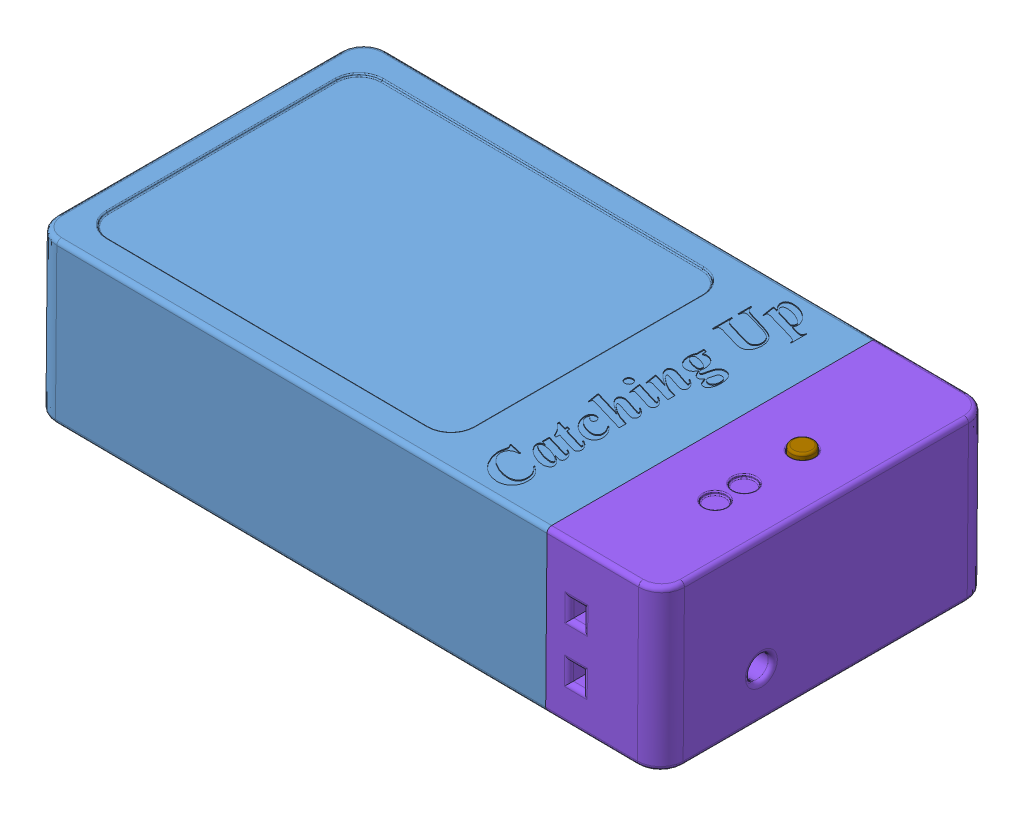
SolidWorks assembly Assemblage2, configuration Défaut. Lengths in mm.
Overall size (137.3 36.19 72).
11 component instances, 9 part files, 7 mates.
Components (placement in the parent):
- boitierHaut-1: boitierHaut [Défaut] at (21.3672 20.9125 31) x (-0.999962 0.008727 0) z (0 0 1) size (119 35 72)
- Assemblage3-1: Assemblage3 [Défaut] at (-20.9673 14.1434 2.8937) x (-0.999962 0.008727 0) z (-0.000152 -0.017452 -0.999848) size (120.99 30.31 52.25)
  - bouton-1: bouton [Défaut] at (-61.2589 -5.3974 3.7359) x (0 0.017452 0.999848) z (-1 0 0) size (13 7.1 12)
  - circuit-1: circuit [Défaut] at (-60.3389 -5.8468 -22.0102) x (1 0 0) z (0 -0.999848 0.017452) size (50 50 1.6)
  - lecteur rfid-1: lecteur rfid [Défaut] at (-17.2739 1.0424 28.8799) x (1 0 0) z (0 0.017452 0.999848) size (112 15 52)
  - module rf-1: module rf [Défaut] at (-26.2716 -8.8392 12.8286) x (1 0 0) z (0 -0.017452 -0.999848) size (29 15 15)
  - red-led-5mm-1: red-led-5mm [Default] at (-55.2587 -4.9394 -2.9734) x (1 0 0) z (0 0.999848 -0.017452) size (5.95 5.62 28.7)
  - User Library-ArduinoMicro-1: User Library-ArduinoMicro [Default] at (-37.4535 -9.5207 4.728) x (0 -0.017452 -0.999848) z (-1 0 0) size (49.28 17.35 17.83)
  - red-led-5mm-2: red-led-5mm [Default] at (-55.2588 -5.0502 -9.3222) x (1 0 0) z (0 0.999848 -0.017452) size (5.95 5.62 28.7)
- Pièce2^Assemblage2-1: Pièce2^Assemblage2 [Défaut] at (21.1098 -8.5864 31) x (-0.999962 0.008727 0) z (-0.008727 -0.999962 0) size (135 72 35) (virtual)
- Pièce1^Assemblage2-1: Pièce1^Assemblage2 [Défaut] at (-69.4127 21.7047 0) x (0.999962 -0.008727 0) z (0.008727 0.999962 0) size (5.69 5.69 10) (virtual)
Mates (geometry in assembly coordinates):
- Coïncidente8: coincident anti-aligned: plane of boitierHaut-1 through (21.3236 15.9126 31) normal (-0.008727 -0.999962 0); plane of Assemblage3-1/lecteur rfid-1 through (-3.6755 16.1308 -26) normal (0.008727 0.999962 0)
- Coïncidente9: coincident anti-aligned: plane of boitierHaut-1 through (-80.6289 21.8026 31) normal (0.999962 -0.008727 0); plane of Assemblage3-1/lecteur rfid-1 through (-80.6725 16.8028 -26) normal (-0.999962 0.008727 0)
- Distance3: distance = 0.5 mm anti-aligned: plane of boitierHaut-1 through (-80.69 14.8028 -26.5) normal (0 0 1); plane of Assemblage3-1/lecteur rfid-1 through (-3.6755 16.1308 -26) normal (0 0 -1)
- Coaxiale1: concentric anti-aligned: cylinder of Pièce2^Assemblage2-1 through (34.0463 -14.2005 -6.7475) axis (0.008727 0.999962 0) radius 2.6; cylinder of Pièce1^Assemblage2-1 through (34.3605 21.7991 -6.7475) axis (-0.008727 -0.999962 0) radius 2.45
- Coïncidente4: coincident anti-aligned: plane of Assemblage3-1/bouton-1 through (34.2732 11.7995 -6.7475) normal (0.008727 0.999962 0); plane of Pièce1^Assemblage2-1 through (34.2732 11.7995 -6.7475) normal (-0.008727 -0.999962 0)
- Coïncidente6: coincident anti-aligned: line of boitierHaut-1 through (21.3672 20.9125 -35) axis (0 0 1); line of Pièce2^Assemblage2-1 through (21.3672 20.9125 35) axis (0 0 -1)
- Coïncidente7: coincident aligned: line of boitierHaut-1 through (21.3585 19.9125 -36) axis (-0.008727 -0.999962 0); line of Pièce2^Assemblage2-1 through (21.3585 19.9125 -36) axis (-0.008727 -0.999962 0)
